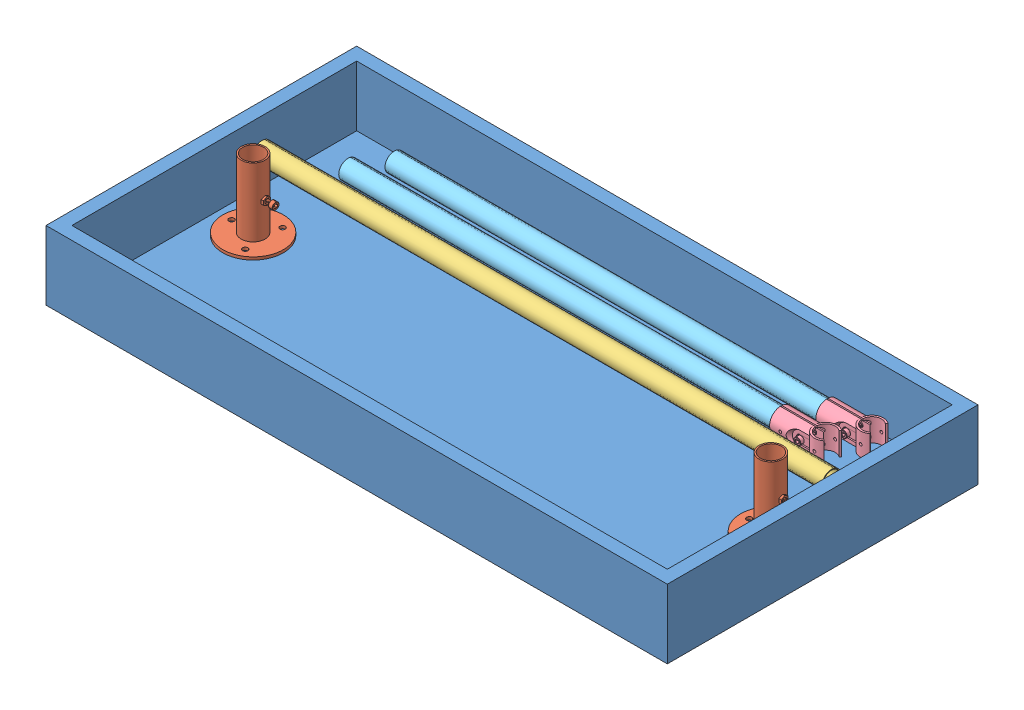
SolidWorks assembly 1001-Transport, configuration Default. Lengths in mm.
Overall size (914.4 117.35 457.2).
12 component instances, 5 part files, 1 mates.
Components (placement in the parent):
- 1100-BaseAsm-1: 1100-BaseAsm [Default] at origin size (914.4 117.35 457.2)
  - 6001-Base-1: 6001-Base [Default] at origin size (914.4 101.6 457.2)
  - 6005-ClampFitting-4: 6005-ClampFitting [2534T82] at (838.2 0 -228.6) x (1 0 0) z (0 1 0) size (88.9 88.9 104.65)
  - 6005-ClampFitting-5: 6005-ClampFitting [2534T82] at (76.2 0 -228.6) x (1 0 0) z (0 1 0) size (88.9 88.9 104.65)
- 1150-TopAsm-1: 1150-TopAsm [Default] at (-176.6102 -350.1614 -66.1248) x (0 0 -1) z (1 0 0) size (27.43 27.43 838.2)
  - 6020-PipeTop-1: 6020-PipeTop [2534T132] at (232.6468 393.9256 614.7602) size (27.43 27.43 838.2)
- 1120-Post-1: 1120-Post [Default] at (66.182 85.8413 -120.6356) x (0 -1 0) z (0 0 1) size (33.53 713.41 34.1)
  - 6015-ClampOpen-1: 6015-ClampOpen [2534T22] at (63.1228 720.8951 -239.7753) size (33.53 76.2 34.1)
  - 6010-PipeSide-3: 6010-PipeSide [2534T132] at (63.1228 348.0978 -239.7753) x (1 0 0) z (0 1 0) size (27.43 27.43 660.4)
- 1120-Post-2: 1120-Post [Default] at (90.7527 85.5662 -164.1164) x (0 -1 0) z (0 0 1) size (33.53 713.41 34.1)
  - 6015-ClampOpen-1: 6015-ClampOpen [2534T22] at (63.1228 720.8951 -239.7753) size (33.53 76.2 34.1)
  - 6010-PipeSide-3: 6010-PipeSide [2534T132] at (63.1228 348.0978 -239.7753) x (1 0 0) z (0 1 0) size (27.43 27.43 660.4)
Mates (geometry in assembly coordinates):
- Coincident6: coincident aligned: plane of 1100-BaseAsm-1/6001-Base-1 through (19.05 88.9 -19.05) normal (1 0 0); circle of 1150-TopAsm-1/6020-PipeTop-1
